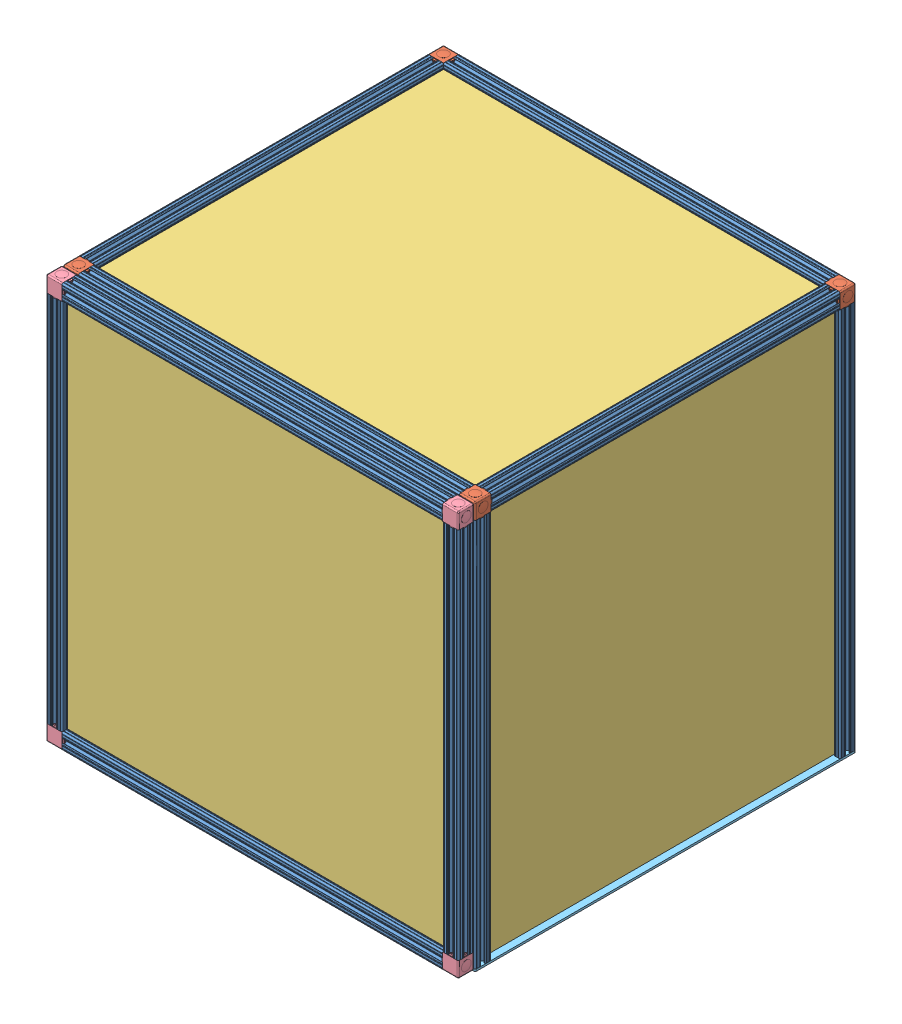
SolidWorks assembly Enclosure, configuration Default. Lengths in mm.
Overall size (661.45 651.4 637.02).
32 component instances, 8 part files, 77 mates.
Components (placement in the parent):
- Aluminum Extrusion-2: Aluminum Extrusion [22in] at (317.4 638.075 0) size (25.4 25.4 558.8)
- Aluminum Extrusion-3: Aluminum Extrusion [24in] at (0 638.075 292) x (0 0 -1) z (1 0 0) size (25.4 25.4 609.6)
- Aluminum Extrusion-4: Aluminum Extrusion [24in] at (0 638.075 -292) x (0 0 -1) z (1 0 0) size (25.4 25.4 609.6)
- Aluminum Extrusion-5: Aluminum Extrusion [22in] at (-317.4 638.075 0) size (25.4 25.4 558.8)
- Aluminum Extrusion-6: Aluminum Extrusion [24.5in] at (317.4 314.325 -292) x (1 0 0) z (0 -1 0) size (25.4 25.4 622.3)
- Aluminum Extrusion-7: Aluminum Extrusion [24.5in] at (317.4 314.325 292) x (1 0 0) z (0 -1 0) size (25.4 25.4 622.3)
- Aluminum Extrusion-8: Aluminum Extrusion [24.5in] at (-317.4 314.325 -292) x (1 0 0) z (0 -1 0) size (25.4 25.4 622.3)
- Aluminum Extrusion-9: Aluminum Extrusion [24.5in] at (-317.4 314.325 292) x (1 0 0) z (0 -1 0) size (25.4 25.4 622.3)
- 3-Way Corner Bracket-1: 3-Way Corner Bracket [47065T244] at (304.8 625.475 279.4) size (28.42 28.42 28.42)
- 3-Way Corner Bracket-2: 3-Way Corner Bracket [47065T244] at (-304.8 625.475 279.4) x (0 0 1) z (-1 0 0) size (28.42 28.42 28.42)
- 3-Way Corner Bracket-3: 3-Way Corner Bracket [47065T244] at (-304.8 625.475 -279.4) x (-1 0 0) z (0 0 -1) size (28.42 28.42 28.42)
- 3-Way Corner Bracket-4: 3-Way Corner Bracket [47065T244] at (304.8 625.475 -279.4) x (1 0 0) z (0 1 0) size (28.42 28.42 28.42)
- PC Sheet-1: PC Sheet [Front] at (0 327.025 318.9994) size (621.6 608.9 3.17)
- PC Sheet-3: PC Sheet [Side] at (317.4 317.325 0) x (0 0 -1) z (1 0 0) size (570.8 628.3 3.17)
- PC Sheet-5: PC Sheet [Top] at (0 638.075 0) x (1 0 0) z (0 1 0) size (621.6 570.8 3.17)
- PC Sheet-7: PC Sheet [Side] at (-317.4 317.325 0) x (0 0 -1) z (1 0 0) size (570.8 628.3 3.17)
- Aluminum Extrusion-10: Aluminum Extrusion [24in] at (0 638.075 318.9994) x (0 1 0) z (1 0 0) size (25.4 25.4 609.6)
- Aluminum Extrusion-11: Aluminum Extrusion [23.5in] at (317.4 327.025 318.9994) x (1 0 0) z (0 -1 0) size (25.4 25.4 596.9)
- Aluminum Extrusion-12: Aluminum Extrusion [23.5in] at (-317.4 327.025 318.9994) x (0 0 -1) z (0 -1 0) size (25.4 25.4 596.9)
- Aluminum Extrusion-13: Aluminum Extrusion [24in] at (0 15.975 318.9994) x (0 0 -1) z (1 0 0) size (25.4 25.4 609.6)
- 2-Way Corner Bracket-1: 2-Way Corner Bracket [47065T242] at (-304.8 625.475 318.9994) x (0 0 -1) z (0 1 0) size (25.2 28.42 28.42)
- 2-Way Corner Bracket-2: 2-Way Corner Bracket [47065T242] at (-304.8 28.575 318.9994) x (0 0 -1) z (-1 0 0) size (25.2 28.42 28.42)
- 2-Way Corner Bracket-3: 2-Way Corner Bracket [47065T242] at (304.8 28.575 318.9994) x (0 0 1) z (1 0 0) size (25.2 28.42 28.42)
- 2-Way Corner Bracket-4: 2-Way Corner Bracket [47065T242] at (304.8 625.475 318.9994) x (0 0 -1) z (1 0 0) size (25.2 28.42 28.42)
- PC Sheet-8: PC Sheet [Back] at (0 317.325 -292) size (621.6 628.3 3.17)
- 47065T347_T-Slotted Framing-2: 47065T347_T-Slotted Framing [47065T347] at (-330.1 85.725 305.4997) x (0 0 1) z (-1 0 0) (suppressed, hidden)
- 47065T347_T-Slotted Framing-3: 47065T347_T-Slotted Framing [47065T347] at (-330.1 568.325 305.4997) x (0 0 -1) z (-1 0 0) (suppressed, hidden)
- 1078A311_Plastic Unthreaded-Hole Rectangular Pull Handle-1: 1078A311_Plastic Unthreaded-Hole Rectangular Pull Handle [1078A311] at (317.4 327.025 331.6994) x (0 1 0) z (0 0 1) (suppressed, hidden)
- Bottom Plate-1: Bottom Plate [Default] x (0 0 -1) z (1 0 0) size (609.6 3.17 660.4)
- Aluminum Extrusion-14: Aluminum Extrusion [24in] at (0 15.875 292) x (0 1 0) z (1 0 0) size (25.4 25.4 609.6)
- 47065T236_Silver Corner Bracket-1: 47065T236_Silver Corner Bracket [47065T236] at (-304.7 28.575 292) (suppressed, hidden)
- 47065T236_Silver Corner Bracket-2: 47065T236_Silver Corner Bracket [47065T236] at (304.7 28.575 292) x (-1 0 0) z (0 0 -1) (suppressed, hidden)
Mates (geometry in assembly coordinates):
- Concentric1: concentric anti-aligned: circle of Aluminum Extrusion-2; circle of Corner End Bracket-1
- Coincident13: coincident anti-aligned: plane of Aluminum Extrusion-2 through (319.1093 630.4042 279.4) normal (0 0 1); plane of 3-Way Corner Bracket-1 through (304.8 650.675 279.4) normal (0 0 -1)
- Concentric4: concentric anti-aligned: circle of Corner End Bracket-1; circle of Aluminum Extrusion-7
- Coincident14: coincident anti-aligned: plane of Aluminum Extrusion-7 through (319.1093 625.475 284.3292) normal (0 1 0); plane of 3-Way Corner Bracket-1 through (304.8 625.475 304.6) normal (0 -1 0)
- Concentric5: concentric aligned: circle of Aluminum Extrusion-3; circle of Corner End Bracket-1
- Coincident15: coincident anti-aligned: plane of Aluminum Extrusion-3 through (304.8 630.4042 290.2907) normal (1 0 0); plane of 3-Way Corner Bracket-1 through (304.8 650.675 279.4) normal (-1 0 0)
- Concentric6: concentric aligned: circle of Aluminum Extrusion-3; circle of Corner End Bracket-2
- Coincident16: coincident anti-aligned: plane of Aluminum Extrusion-3 through (-304.8 630.4042 290.2907) normal (-1 0 0); plane of 3-Way Corner Bracket-2 through (-304.8 650.675 279.4) normal (1 0 0)
- Concentric7: concentric anti-aligned: circle of Aluminum Extrusion-9; circle of Corner End Bracket-2
- Coincident17: coincident anti-aligned: plane of Aluminum Extrusion-9 through (-315.6907 625.475 284.3292) normal (0 1 0); plane of 3-Way Corner Bracket-2 through (-330 625.475 279.4) normal (0 -1 0)
- Concentric8: concentric aligned: circle of Aluminum Extrusion-5; circle of Corner End Bracket-2
- Coincident18: coincident anti-aligned: plane of Aluminum Extrusion-5 through (-315.6907 630.4042 279.4) normal (0 0 1); plane of 3-Way Corner Bracket-2 through (-304.8 650.675 279.4) normal (0 0 -1)
- Concentric9: concentric aligned: circle of Aluminum Extrusion-5; circle of Corner End Bracket-3
- Coincident19: coincident anti-aligned: plane of Aluminum Extrusion-5 through (-315.6907 630.4042 -279.4) normal (0 0 -1); plane of 3-Way Corner Bracket-3 through (-304.8 650.675 -279.4) normal (0 0 1)
- Concentric10: concentric anti-aligned: circle of Aluminum Extrusion-8; circle of Corner End Bracket-3
- Coincident20: coincident anti-aligned: plane of Aluminum Extrusion-8 through (-315.6907 625.475 -299.6708) normal (0 1 0); plane of 3-Way Corner Bracket-3 through (-304.8 625.475 -304.6) normal (0 -1 0)
- Concentric11: concentric anti-aligned: circle of Aluminum Extrusion-4; circle of Corner End Bracket-3
- Coincident21: coincident anti-aligned: plane of Aluminum Extrusion-4 through (-304.8 630.4042 -293.7093) normal (-1 0 0); plane of 3-Way Corner Bracket-3 through (-304.8 650.675 -279.4) normal (1 0 0)
- Concentric12: concentric anti-aligned: circle of Aluminum Extrusion-2; circle of Corner End Bracket-4
- Coincident22: coincident anti-aligned: plane of Aluminum Extrusion-2 through (319.1093 630.4042 -279.4) normal (0 0 -1); plane of 3-Way Corner Bracket-4 through (304.8 650.675 -279.4) normal (0 0 1)
- Concentric13: concentric aligned: circle of Aluminum Extrusion-6; circle of Corner End Bracket-4
- Coincident23: coincident anti-aligned: plane of Aluminum Extrusion-6 through (319.1093 625.475 -299.6708) normal (0 1 0); plane of 3-Way Corner Bracket-4 through (304.8 625.475 -304.6) normal (0 -1 0)
- Coincident27: coincident aligned: plane of Aluminum Extrusion-2 through (317.4 638.075 0) normal (0 0 1)
- Coincident28: coincident aligned: plane of Aluminum Extrusion-3 through (0 638.075 292) normal (1 0 0)
- Width1: width aligned: plane of PC Sheet-1 through (0 327.025 320.5869) normal (0 0 1); plane of Aluminum Extrusion-12 through (0 327.025 317.4119) normal (0 0 -1); plane of PC Sheet-1 through (-323.7331 28.575 331.6994) normal (0 0 1); plane of Aluminum Extrusion-12 through (-326.9504 28.575 306.2994) normal (0 0 -1)
- Coincident29: coincident aligned: plane of assembly through (0 0 0) normal (1 0 0); plane of PC Sheet-1 through (0 327.025 318.9994) normal (1 0 0)
- Coincident31: coincident anti-aligned: plane of 2-Way Corner Bracket-1 through (-304.8 631.475 322.2494) normal (0 -1 0); plane of PC Sheet-1 through (310.8 631.475 320.5869) normal (0 1 0)
- Coincident32: coincident anti-aligned: plane of PC Sheet-3 through (317.4 317.325 0) normal (0 0 -1); plane of Aluminum Extrusion-2 through (317.4 638.075 0) normal (0 0 1)
- Width2: width aligned: plane of PC Sheet-3 through (318.9875 317.325 0) normal (1 0 0); plane of Aluminum Extrusion-7 through (315.8125 317.325 0) normal (-1 0 0); plane of PC Sheet-3 through (330.1 3.175 282.4496) normal (1 0 0); plane of Aluminum Extrusion-7 through (304.7 3.175 285.6669) normal (-1 0 0)
- Coincident33: coincident anti-aligned: plane of 3-Way Corner Bracket-1 through (320.65 631.475 285.4) normal (0 -1 0); plane of PC Sheet-3 through (318.9875 631.475 -285.4) normal (0 1 0)
- Width3: width aligned: plane of PC Sheet-5 through (0 639.6625 0) normal (0 1 0); plane of Aluminum Extrusion-2 through (0 636.4875 0) normal (0 -1 0); plane of PC Sheet-5 through (326.9504 650.775 279.4) normal (0 1 0); plane of Aluminum Extrusion-2 through (323.7331 625.375 279.4) normal (0 -1 0)
- Coincident34: coincident anti-aligned: plane of Bottom Plate-1 through (0 0 0) normal (0 -1 0); plane of assembly through (0 0 0) normal (0 1 0)
- Width4: width aligned: plane of PC Sheet-5 through (0 639.6625 0) normal (0 1 0); plane of Aluminum Extrusion-2 through (0 636.4875 0) normal (0 -1 0); plane of PC Sheet-5 through (326.9504 650.775 279.4) normal (0 1 0); plane of Aluminum Extrusion-2 through (323.7331 625.375 279.4) normal (0 -1 0)
- Coincident37: coincident anti-aligned: plane of Aluminum Extrusion-5 through (-317.4 638.075 0) normal (0 0 1); plane of PC Sheet-5 through (0 638.075 0) normal (0 0 -1)
- Coincident38: coincident aligned: plane of Aluminum Extrusion-3 through (0 638.075 292) normal (1 0 0); plane of PC Sheet-5 through (0 638.075 0) normal (1 0 0)
- Coincident39: coincident aligned: plane of Aluminum Extrusion-10 through (304.8 647.6254 331.6994) normal (0 0 1); plane of Aluminum Extrusion-12 through (-323.7331 28.575 331.6994) normal (0 0 1)
- Coincident40: coincident aligned: plane of Aluminum Extrusion-11 through (311.0669 28.575 331.6994) normal (0 0 1); plane of Aluminum Extrusion-12 through (-323.7331 28.575 331.6994) normal (0 0 1)
- Coincident41: coincident aligned: plane of Aluminum Extrusion-11 through (326.9504 28.575 331.6994) normal (0 0 1); plane of Aluminum Extrusion-13 through (304.8 25.5254 331.6994) normal (0 0 1)
- Concentric14: concentric anti-aligned: circle of Aluminum Extrusion-10; circle of 2-Way Corner Bracket-1
- Concentric15: concentric aligned: circle of Aluminum Extrusion-12; circle of 2-Way Corner Bracket-1
- Coincident42: coincident anti-aligned: plane of Aluminum Extrusion-10 through (-304.8 639.7843 311.3286) normal (-1 0 0); plane of 2-Way Corner Bracket-1 through (-304.8 650.675 331.5994) normal (1 0 0)
- Coincident43: coincident anti-aligned: plane of Aluminum Extrusion-12 through (-325.0708 625.475 317.2901) normal (0 1 0); plane of 2-Way Corner Bracket-1 through (-330 625.475 331.5994) normal (0 -1 0)
- Width6: width: plane of Aluminum Extrusion-9 through (-326.1371 3.175 299.1294) normal (-0.706297 0 -0.707915); plane of Aluminum Extrusion-9 through (-322.841 3.175 288.1592) normal (-0.706297 0 0.707915); cylinder of 47065T347_T-Slotted Framing-2 through (-330.1 98.425 292) axis (1 0 0) radius 3.25
- Coincident45: coincident aligned: plane of Aluminum Extrusion-9 through (-330.1 3.175 301.5504) normal (-1 0 0); plane of Aluminum Extrusion-12 through (-330.1 28.575 312.6662) normal (-1 0 0)
- Coincident46: coincident aligned: plane of Aluminum Extrusion-3 through (304.8 650.775 298.3331) normal (0 1 0); plane of Aluminum Extrusion-10 through (304.8 650.775 309.449) normal (0 1 0)
- Concentric16: concentric aligned: circle of Aluminum Extrusion-12; circle of 2-Way Corner Bracket-2
- Concentric17: concentric aligned: circle of 2-Way Corner Bracket-2; circle of Aluminum Extrusion-13
- Coincident47: coincident anti-aligned: plane of Aluminum Extrusion-13 through (-304.8 8.3042 317.2901) normal (-1 0 0); plane of 2-Way Corner Bracket-2 through (-304.8 3.375 331.5994) normal (1 0 0)
- Coincident48: coincident anti-aligned: plane of Aluminum Extrusion-12 through (-325.0708 28.575 317.2901) normal (0 -1 0); plane of 2-Way Corner Bracket-2 through (-330 28.575 331.5994) normal (0 1 0)
- Concentric18: concentric aligned: circle of Aluminum Extrusion-11; circle of 2-Way Corner Bracket-3
- Concentric19: concentric anti-aligned: circle of Aluminum Extrusion-13; circle of 2-Way Corner Bracket-3
- Coincident49: coincident anti-aligned: plane of Aluminum Extrusion-13 through (304.8 8.3042 317.2901) normal (1 0 0); plane of 2-Way Corner Bracket-3 through (304.8 3.375 306.3994) normal (-1 0 0)
- Coincident50: coincident anti-aligned: plane of Aluminum Extrusion-11 through (319.1093 28.575 311.3286) normal (0 -1 0); plane of 2-Way Corner Bracket-3 through (330 28.575 306.3994) normal (0 1 0)
- Concentric20: concentric anti-aligned: circle of Aluminum Extrusion-11; circle of 2-Way Corner Bracket-4
- Concentric22: concentric anti-aligned: circle of Aluminum Extrusion-10; circle of 2-Way Corner Bracket-4
- Width5: width aligned: plane of PC Sheet-8 through (0 317.325 -290.4125) normal (0 0 1); plane of PC Sheet-8 through (0 317.325 -293.5875) normal (0 0 -1); plane of Aluminum Extrusion-6 through (311.0669 3.175 -279.3) normal (0 0 1); plane of Aluminum Extrusion-6 through (307.8496 3.175 -304.7) normal (0 0 -1)
- Coincident51: coincident anti-aligned: plane of 3-Way Corner Bracket-4 through (304.8 631.475 -295.25) normal (0 -1 0); plane of PC Sheet-8 through (310.8 631.475 -290.4125) normal (0 1 0)
- Coincident52: coincident aligned: plane of Aluminum Extrusion-4 through (0 638.075 -292) normal (1 0 0); plane of PC Sheet-8 through (0 317.325 -292) normal (1 0 0)
- Width7: width: plane of Aluminum Extrusion-12 through (-326.0452 28.575 326.179) normal (-0.707751 0 -0.706462); plane of Aluminum Extrusion-12 through (-322.8237 28.575 315.0471) normal (-0.707751 0 0.706462); cylinder of 47065T347_T-Slotted Framing-2 through (-330.1 98.425 318.9994) axis (1 0 0) radius 3.25
- Width8: width: plane of Aluminum Extrusion-12 through (-326.0452 28.575 326.179) normal (-0.707751 0 -0.706462); plane of Aluminum Extrusion-12 through (-322.8237 28.575 315.0471) normal (-0.707751 0 0.706462); cylinder of 47065T347_T-Slotted Framing-2 through (-330.1 73.025 318.9994) axis (1 0 0) radius 3.25
- Coincident53: coincident anti-aligned: plane of Aluminum Extrusion-9 through (-330.1 3.175 285.6669) normal (-1 0 0); plane of 47065T347_T-Slotted Framing-2 through (-330.1 79.375 301.353) normal (1 0 0)
- Coincident54: coincident anti-aligned: plane of Aluminum Extrusion-11 through (311.0669 28.575 331.6994) normal (0 0 1); plane of 1078A311_Plastic Unthreaded-Hole Rectangular Pull Handle-1 through (306.2875 364.3003 331.6994) normal (0 0 -1)
- Symmetric1: symmetric aligned: plane of Aluminum Extrusion-11 through (317.4 327.025 318.9994) normal (1 0 0); plane of 1078A311_Plastic Unthreaded-Hole Rectangular Pull Handle-1 through (306.2875 362.0845 363.4494) normal (-1 0 0); plane of 1078A311_Plastic Unthreaded-Hole Rectangular Pull Handle-1 through (328.5125 362.0845 363.4494) normal (1 0 0)
- Coincident55: coincident anti-aligned: plane of Aluminum Extrusion-11 through (317.4 327.025 318.9994) normal (0 -1 0); plane of 1078A311_Plastic Unthreaded-Hole Rectangular Pull Handle-1 through (317.4 327.025 331.6994) normal (0 1 0)
- Distance2: distance = 431.8 mm anti-aligned: plane of 47065T347_T-Slotted Framing-2 through (-330.1 111.125 301.353) normal (0 1 0); plane of 47065T347_T-Slotted Framing-3 through (-332.8688 542.925 320.5774) normal (0 -1 0)
- Concentric23: concentric aligned: circle of Aluminum Extrusion-6; circle of Bottom Plate-1
- Concentric24: concentric aligned: circle of Aluminum Extrusion-7; circle of Bottom Plate-1
- Coincident58: coincident anti-aligned: plane of Aluminum Extrusion-6 through (319.1093 3.175 -299.6708) normal (0 -1 0); plane of Bottom Plate-1 through (0 3.175 0) normal (0 1 0)
- Coincident59: coincident aligned: plane of Aluminum Extrusion-7 through (307.8496 3.175 279.3) normal (0 0 -1); plane of Aluminum Extrusion-14 through (304.8 22.2081 279.3) normal (0 0 -1)
- Coincident60: coincident anti-aligned: plane of Bottom Plate-1 through (0 3.175 0) normal (0 1 0); plane of Aluminum Extrusion-14 through (304.8 3.175 285.6669) normal (0 -1 0)
- Coincident61: coincident aligned: plane of Aluminum Extrusion-14 through (0 15.875 292) normal (1 0 0); plane of Aluminum Extrusion-3 through (0 638.075 292) normal (1 0 0)
- Coincident62: coincident anti-aligned: plane of Aluminum Extrusion-9 through (-304.7 3.175 282.4496) normal (1 0 0); plane of 47065T236_Silver Corner Bracket-1 through (-304.7 28.575 303.1125) normal (-1 0 0)
- Coincident63: coincident anti-aligned: plane of Aluminum Extrusion-14 through (304.8 28.575 298.3331) normal (0 1 0); plane of 47065T236_Silver Corner Bracket-1 through (-279.3 28.575 303.1125) normal (0 -1 0)
- Width9: width: plane of Aluminum Extrusion-9 through (-307.8496 3.175 304.7) normal (0 0 1); plane of 47065T236_Silver Corner Bracket-1 through (-311.0669 3.175 279.3) normal (0 0 -1); cylinder of Aluminum Extrusion-9 through (-279.3 41.275 292) axis (-1 0 0) radius 3.5687
- Coincident64: coincident anti-aligned: plane of Aluminum Extrusion-14 through (304.8 28.575 298.3331) normal (0 1 0); plane of 47065T236_Silver Corner Bracket-2 through (279.3 28.575 280.8875) normal (0 -1 0)
- Coincident65: coincident anti-aligned: plane of Aluminum Extrusion-7 through (304.7 3.175 301.5504) normal (-1 0 0); plane of 47065T236_Silver Corner Bracket-2 through (304.7 28.575 280.8875) normal (1 0 0)
- Width10: width: plane of Aluminum Extrusion-7 through (326.9504 3.175 304.7) normal (0 0 1); plane of 47065T236_Silver Corner Bracket-2 through (307.8496 3.175 279.3) normal (0 0 -1); cylinder of Aluminum Extrusion-7 through (279.3 41.275 292) axis (1 0 0) radius 3.5687
